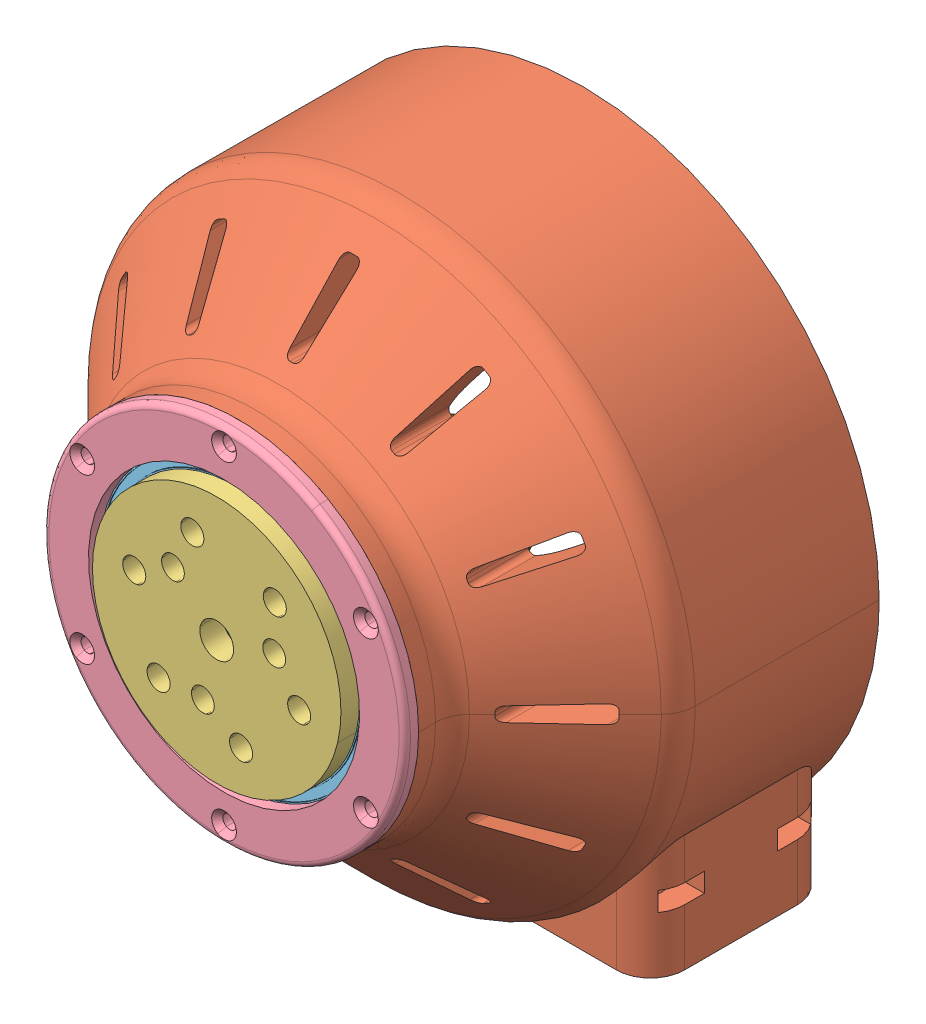
SolidWorks assembly SpryDrive 8318, configuration Default. Lengths in mm.
Overall size (105 105 68.81).
71 component instances, 27 part files, 0 mates.
Components (placement in the parent):
- sprydrive 8318.STEP-1: sprydrive 8318.STEP [Default] at origin size (130.11 130.11 77.91)
  - MOTOR BACK HOUSING REV01.STEP-1: MOTOR BACK HOUSING REV01.STEP [Default] at (0 0 6) x (0.707107 0.707107 0) z (-0.707107 0.707107 0) size (92 25.2 92) (hidden)
  - MOTOR ROTOR REV01_X8318S.STEP-1: MOTOR ROTOR REV01_X8318S.STEP [Default] at (0 0 6.3) x (-0.302803 -0.953053 0) z (-0.953053 0.302803 0) size (92 33.71 92) (hidden)
  - MOTOR STATOR REV01.STEP-1: MOTOR STATOR REV01.STEP [Default] at (0 0 7.2) x (-0.996782 0.080159 0) z (0.080159 0.996782 0) size (81.2 19.01 81.2) (hidden)
  - MOTOR SHAFT REV01_X8318S.STEP-1: MOTOR SHAFT REV01_X8318S.STEP [Default] at (0 0 3.5) x (0.302803 0.953053 0) z (0.953053 -0.302803 0) size (19.64 50.01 18.94)
  - FRAME REV07_X8318S.STEP-1: FRAME REV07_X8318S.STEP [Default] at origin size (105 105 61.05)
  - OUTPUT PLATE REV05.STEP-1: OUTPUT PLATE REV05.STEP [Default] at (0 0 60.725) x (-0.973223 0.229863 0) z (0 0 1) size (44 44 11.85)
  - BACK PLATE REV05.STEP-1: BACK PLATE REV05.STEP [Default] x (-1 0 0) z (0 -1 0) size (105 7 105) (hidden)
  - BEARING COVER REV04.STEP-1: BEARING COVER REV04.STEP [Default] at (0 0 61.5) x (-0.5 -0.866025 0) z (0 0 1) size (64 64 2.45)
  - ADAPTER PLATE REV05.STEP-1: ADAPTER PLATE REV05.STEP [Default] at (0 0 40) x (-0.953053 0.302803 0) z (0 0 1) size (37 37 3.17) (hidden)
  - MAGNET HOLDER REV02.STEP-1: MAGNET HOLDER REV02.STEP [Default] at (0 0 -2) x (0.97677 0.214292 0) z (0 0 -1) size (24 24 5) (hidden)
  - ENCODER MOUNT REV01.STEP-1: ENCODER MOUNT REV01.STEP [Default] x (-1 0 0) z (0 -1 0) size (35.15 5.5 30) (hidden)
  - 91294A190_BLACK ALLOY STEEL FLAT-HEAD SOCKET CAP SCREW_91294A190.STEP-1: 91294A190_BLACK ALLOY STEEL FLAT-HEAD SOCKET CAP SCREW_91294A190.STEP [Default] at (-20 0 -6.6) x (-1 0 0) z (0 0 -1) size (8 8 10.01) (hidden)
  - 91294A190_BLACK ALLOY STEEL FLAT-HEAD SOCKET CAP SCREW_91294A190.STEP-2: 91294A190_BLACK ALLOY STEEL FLAT-HEAD SOCKET CAP SCREW_91294A190.STEP [Default] at (0 20 -6.6) x (-1 0 0) z (0 0 -1) size (8 8 10.01) (hidden)
  - 91294A190_BLACK ALLOY STEEL FLAT-HEAD SOCKET CAP SCREW_91294A190.STEP-3: 91294A190_BLACK ALLOY STEEL FLAT-HEAD SOCKET CAP SCREW_91294A190.STEP [Default] at (20 0 -6.6) x (-1 0 0) z (0 0 -1) size (8 8 10.01) (hidden)
  - 93395A144_TYPE 316 SS FLAT-HEAD SOCKET CAP SCREW_93395A144.STEP-1: 93395A144_TYPE 316 SS FLAT-HEAD SOCKET CAP SCREW_93395A144.STEP [Default] at (14.0729 8.125 -12.5) x (-1 0 0) z (0 0 -1) size (4 4 10) (hidden)
  - 93395A144_TYPE 316 SS FLAT-HEAD SOCKET CAP SCREW_93395A144.STEP-2: 93395A144_TYPE 316 SS FLAT-HEAD SOCKET CAP SCREW_93395A144.STEP [Default] at (-14.0729 8.125 -12.5) x (-1 0 0) z (0 0 -1) size (4 4 10) (hidden)
  - 93395A144_TYPE 316 SS FLAT-HEAD SOCKET CAP SCREW_93395A144.STEP-3: 93395A144_TYPE 316 SS FLAT-HEAD SOCKET CAP SCREW_93395A144.STEP [Default] at (-14.0729 -8.125 -12.5) x (-1 0 0) z (0 0 -1) size (4 4 10) (hidden)
  - 93395A144_TYPE 316 SS FLAT-HEAD SOCKET CAP SCREW_93395A144.STEP-4: 93395A144_TYPE 316 SS FLAT-HEAD SOCKET CAP SCREW_93395A144.STEP [Default] at (14.0729 -8.125 -12.5) x (-1 0 0) z (0 0 -1) size (4 4 10) (hidden)
  - 6808-2RS BEARING DEEP GROOVE 40x52x7 REV02_4668K161.STEP-1: 6808-2RS BEARING DEEP GROOVE 40x52x7 REV02_4668K161.STEP [Default] at (0 0 58) x (0.843788 0.536676 0) z (0 0 -1) size (52 52 7)
  - AS5048A-AB-1.0-ND ENCODER BOARD.STEP-1: AS5048A-AB-1.0-ND ENCODER BOARD.STEP [Default] at (0 -6.5 -10) x (-1 0 0) z (0 1 0) size (22 2 28) (hidden)
  - AS5048A-AB-1.0-ND MAGNET.STEP-1: AS5048A-AB-1.0-ND MAGNET.STEP [Default] at (0 0 -6.5) x (0.996708 0.081075 0) z (0.081075 -0.996708 0) size (6 2.5 6) (hidden)
  - OUTPUT MOUNTING PLATE REV01.STEP-1: OUTPUT MOUNTING PLATE REV01.STEP [Default] at (0 0 57.55) x (0.287545 -0.957767 0) z (0 0 1) size (35 35 3.17)
  - VERSA PLANET.STEP-1: VERSA PLANET.STEP [Default] at (-7.7426 7.2935 48.85) x (-0.918635 0.395106 0) z (0 0 1) size (16.03 16.01 8)
  - VERSA PLANET.STEP-2: VERSA PLANET.STEP [Default] at (10.1876 3.0586 48.85) x (0.461046 0.887376 0) z (0 0 1) size (16.03 16.01 8)
  - VERSA PLANET.STEP-3: VERSA PLANET.STEP [Default] at (-2.445 -10.352 48.85) x (-0.3211 -0.947045 0) z (0 0 1) size (16.03 16.01 8)
  - VERSA RING - MODIFIED.STEP-1: VERSA RING - MODIFIED.STEP [Default] at (0 0 44.1) x (0 1 0) z (0 0 -1) size (42 42 11.32)
  - 93600A455_METRIC TYPE 316 STAINLESS STEEL DOWEL PIN_93600A455.STEP-1: 93600A455_METRIC TYPE 316 STAINLESS STEEL DOWEL PIN_93600A455.STEP [Default] at (-7.7426 7.2935 53.85) x (0 0 -1) z (0.833244 0.552906 0) size (18 4 4) (hidden)
  - 93600A455_METRIC TYPE 316 STAINLESS STEEL DOWEL PIN_93600A455.STEP-2: 93600A455_METRIC TYPE 316 STAINLESS STEEL DOWEL PIN_93600A455.STEP [Default] at (10.1876 3.0586 53.85) x (0 0 -1) z (0.833244 0.552906 0) size (18 4 4) (hidden)
  - 93600A455_METRIC TYPE 316 STAINLESS STEEL DOWEL PIN_93600A455.STEP-3: 93600A455_METRIC TYPE 316 STAINLESS STEEL DOWEL PIN_93600A455.STEP [Default] at (-2.445 -10.352 53.85) x (0 0 -1) z (-0.663244 0.748403 0) size (18 4 4) (hidden)
  - 90358A002_METRIC STL ULTRA-LOW-PROFILE SCKT HEAD SCREW_90358A002.STEP-1: 90358A002_METRIC STL ULTRA-LOW-PROFILE SCKT HEAD SCREW_90358A002.STEP [Default] at (-4.6934 -14.7723 39.175) x (0 0 -1) z (-0.620938 -0.783859 0) size (9.01 5.5 5.5) (hidden)
  - 90358A002_METRIC STL ULTRA-LOW-PROFILE SCKT HEAD SCREW_90358A002.STEP-2: 90358A002_METRIC STL ULTRA-LOW-PROFILE SCKT HEAD SCREW_90358A002.STEP [Default] at (14.7723 -4.6934 39.175) x (0 0 -1) z (-0.964603 -0.263707 0) size (9.01 5.5 5.5) (hidden)
  - 90358A002_METRIC STL ULTRA-LOW-PROFILE SCKT HEAD SCREW_90358A002.STEP-3: 90358A002_METRIC STL ULTRA-LOW-PROFILE SCKT HEAD SCREW_90358A002.STEP [Default] at (4.6934 14.7723 39.175) x (0 0 -1) z (-0.993401 0.11469 0) size (9.01 5.5 5.5) (hidden)
  - 90358A002_METRIC STL ULTRA-LOW-PROFILE SCKT HEAD SCREW_90358A002.STEP-4: 90358A002_METRIC STL ULTRA-LOW-PROFILE SCKT HEAD SCREW_90358A002.STEP [Default] at (-14.7723 4.6934 39.175) x (0 0 -1) z (-0.942672 -0.333722 0) size (9.01 5.5 5.5) (hidden)
  - 93395A144_TYPE 316 SS FLAT-HEAD SOCKET CAP SCREW_93395A144.STEP-5: 93395A144_TYPE 316 SS FLAT-HEAD SOCKET CAP SCREW_93395A144.STEP [Default] at (0 29 63.5) size (4 4 10) (hidden)
  - 93395A144_TYPE 316 SS FLAT-HEAD SOCKET CAP SCREW_93395A144.STEP-6: 93395A144_TYPE 316 SS FLAT-HEAD SOCKET CAP SCREW_93395A144.STEP [Default] at (25.1147 14.5 63.5) size (4 4 10) (hidden)
  - 93395A144_TYPE 316 SS FLAT-HEAD SOCKET CAP SCREW_93395A144.STEP-7: 93395A144_TYPE 316 SS FLAT-HEAD SOCKET CAP SCREW_93395A144.STEP [Default] at (-25.1147 14.5 63.5) size (4 4 10) (hidden)
  - 93395A144_TYPE 316 SS FLAT-HEAD SOCKET CAP SCREW_93395A144.STEP-8: 93395A144_TYPE 316 SS FLAT-HEAD SOCKET CAP SCREW_93395A144.STEP [Default] at (25.1147 -14.5 63.5) size (4 4 10) (hidden)
  - 94459A110_BRASS HEAT-SET INSERT FOR PLASTIC_94459A110.STEP-1: 94459A110_BRASS HEAT-SET INSERT FOR PLASTIC_94459A110.STEP [Default] at (25.1147 14.5 58.55) x (-0.767549 -0.640991 0) z (-0.640991 0.767549 0) size (3.69 2.5 3.69) (hidden)
  - 94459A110_BRASS HEAT-SET INSERT FOR PLASTIC_94459A110.STEP-2: 94459A110_BRASS HEAT-SET INSERT FOR PLASTIC_94459A110.STEP [Default] at (0 29 58.55) x (-0.593469 0.804857 0) z (0.804857 0.593469 0) size (3.69 2.5 3.69) (hidden)
  - 94459A110_BRASS HEAT-SET INSERT FOR PLASTIC_94459A110.STEP-3: 94459A110_BRASS HEAT-SET INSERT FOR PLASTIC_94459A110.STEP [Default] at (0 -29 58.55) x (-0.997114 0.075912 0) z (0.075912 0.997114 0) size (3.69 2.5 3.69) (hidden)
  - 94459A110_BRASS HEAT-SET INSERT FOR PLASTIC_94459A110.STEP-4: 94459A110_BRASS HEAT-SET INSERT FOR PLASTIC_94459A110.STEP [Default] at (25.1147 -14.5 58.55) x (0.079432 0.99684 0) z (0.99684 -0.079432 0) size (3.69 2.5 3.69) (hidden)
  - 93395A144_TYPE 316 SS FLAT-HEAD SOCKET CAP SCREW_93395A144.STEP-9: 93395A144_TYPE 316 SS FLAT-HEAD SOCKET CAP SCREW_93395A144.STEP [Default] at (0 -49.5 -7) x (-1 0 0) z (0 0 -1) size (4 4 10) (hidden)
  - 93395A144_TYPE 316 SS FLAT-HEAD SOCKET CAP SCREW_93395A144.STEP-10: 93395A144_TYPE 316 SS FLAT-HEAD SOCKET CAP SCREW_93395A144.STEP [Default] at (-42.8683 -24.75 -7) x (-1 0 0) z (0 0 -1) size (4 4 10) (hidden)
  - 93395A144_TYPE 316 SS FLAT-HEAD SOCKET CAP SCREW_93395A144.STEP-11: 93395A144_TYPE 316 SS FLAT-HEAD SOCKET CAP SCREW_93395A144.STEP [Default] at (42.8683 -24.75 -7) x (-1 0 0) z (0 0 -1) size (4 4 10) (hidden)
  - 93395A144_TYPE 316 SS FLAT-HEAD SOCKET CAP SCREW_93395A144.STEP-12: 93395A144_TYPE 316 SS FLAT-HEAD SOCKET CAP SCREW_93395A144.STEP [Default] at (0 49.5 -7) x (-1 0 0) z (0 0 -1) size (4 4 10) (hidden)
  - 93395A144_TYPE 316 SS FLAT-HEAD SOCKET CAP SCREW_93395A144.STEP-13: 93395A144_TYPE 316 SS FLAT-HEAD SOCKET CAP SCREW_93395A144.STEP [Default] at (-42.8683 24.75 -7) x (-1 0 0) z (0 0 -1) size (4 4 10) (hidden)
  - 93395A144_TYPE 316 SS FLAT-HEAD SOCKET CAP SCREW_93395A144.STEP-14: 93395A144_TYPE 316 SS FLAT-HEAD SOCKET CAP SCREW_93395A144.STEP [Default] at (42.8683 24.75 -7) x (-1 0 0) z (0 0 -1) size (4 4 10) (hidden)
  - 94459A110_BRASS HEAT-SET INSERT FOR PLASTIC_94459A110.STEP-5: 94459A110_BRASS HEAT-SET INSERT FOR PLASTIC_94459A110.STEP [Default] at (42.8683 -24.75 2.5) x (0.239904 0.970797 0) z (-0.970797 0.239904 0) size (3.69 2.5 3.69) (hidden)
  - 94459A110_BRASS HEAT-SET INSERT FOR PLASTIC_94459A110.STEP-6: 94459A110_BRASS HEAT-SET INSERT FOR PLASTIC_94459A110.STEP [Default] at (0 49.5 2.5) x (0.239904 0.970797 0) z (-0.970797 0.239904 0) size (3.69 2.5 3.69) (hidden)
  - 94459A110_BRASS HEAT-SET INSERT FOR PLASTIC_94459A110.STEP-7: 94459A110_BRASS HEAT-SET INSERT FOR PLASTIC_94459A110.STEP [Default] at (42.8683 24.75 2.5) x (0.239904 0.970797 0) z (-0.970797 0.239904 0) size (3.69 2.5 3.69) (hidden)
  - 94459A110_BRASS HEAT-SET INSERT FOR PLASTIC_94459A110.STEP-8: 94459A110_BRASS HEAT-SET INSERT FOR PLASTIC_94459A110.STEP [Default] at (-42.8683 -24.75 2.5) x (0.239904 0.970797 0) z (-0.970797 0.239904 0) size (3.69 2.5 3.69) (hidden)
  - 94459A110_BRASS HEAT-SET INSERT FOR PLASTIC_94459A110.STEP-9: 94459A110_BRASS HEAT-SET INSERT FOR PLASTIC_94459A110.STEP [Default] at (0 -49.5 2.5) x (0.239904 0.970797 0) z (-0.970797 0.239904 0) size (3.69 2.5 3.69) (hidden)
  - 94459A110_BRASS HEAT-SET INSERT FOR PLASTIC_94459A110.STEP-10: 94459A110_BRASS HEAT-SET INSERT FOR PLASTIC_94459A110.STEP [Default] at (-42.8683 24.75 2.5) x (0.239904 0.970797 0) z (-0.970797 0.239904 0) size (3.69 2.5 3.69) (hidden)
  - 91294A190_BLACK ALLOY STEEL FLAT-HEAD SOCKET CAP SCREW_91294A190.STEP-4: 91294A190_BLACK ALLOY STEEL FLAT-HEAD SOCKET CAP SCREW_91294A190.STEP [Default] at (0 -20 -6.6) x (-1 0 0) z (0 0 -1) size (8 8 10.01) (hidden)
  - 93395A144_TYPE 316 SS FLAT-HEAD SOCKET CAP SCREW_93395A144.STEP-15: 93395A144_TYPE 316 SS FLAT-HEAD SOCKET CAP SCREW_93395A144.STEP [Default] at (0 -29 63.5) size (4 4 10) (hidden)
  - 93395A144_TYPE 316 SS FLAT-HEAD SOCKET CAP SCREW_93395A144.STEP-16: 93395A144_TYPE 316 SS FLAT-HEAD SOCKET CAP SCREW_93395A144.STEP [Default] at (-25.1147 -14.5 63.5) size (4 4 10) (hidden)
  - 90710A025_TYPE 18-8 SS THIN HEX NUT - DIN 439B_90710A025.STEP-1: 90710A025_TYPE 18-8 SS THIN HEX NUT - DIN 439B_90710A025.STEP [Default] at (9 -5.5 -12.3) x (-0.866025 0.5 0) z (-0.5 -0.866025 0) size (5.78 1.62 5.78) (hidden)
  - 90710A025_TYPE 18-8 SS THIN HEX NUT - DIN 439B_90710A025.STEP-2: 90710A025_TYPE 18-8 SS THIN HEX NUT - DIN 439B_90710A025.STEP [Default] at (-9 -5.5 -12.3) x (-0.866025 0.5 0) z (-0.5 -0.866025 0) size (5.78 1.62 5.78) (hidden)
  - 90710A025_TYPE 18-8 SS THIN HEX NUT - DIN 439B_90710A025.STEP-3: 90710A025_TYPE 18-8 SS THIN HEX NUT - DIN 439B_90710A025.STEP [Default] at (-9 5.5 -12.3) x (-0.866025 0.5 0) z (-0.5 -0.866025 0) size (5.78 1.62 5.78) (hidden)
  - 90710A025_TYPE 18-8 SS THIN HEX NUT - DIN 439B_90710A025.STEP-4: 90710A025_TYPE 18-8 SS THIN HEX NUT - DIN 439B_90710A025.STEP [Default] at (9 5.5 -12.3) x (-0.866025 0.5 0) z (-0.5 -0.866025 0) size (5.78 1.62 5.78) (hidden)
  - NMB L2112KK BEARING.STEP-1: NMB L2112KK BEARING.STEP [Default] at (0 0 18.7) x (0.90792 -0.419144 0) z (0 0 1) size (21 21 5)
  - NMB L2112KK BEARING.STEP-2: NMB L2112KK BEARING.STEP [Default] at (0 0 3) x (0.990401 -0.138221 0) z (0 0 1) size (21 21 5)
  - VERSA CARRIER.STEP-1: VERSA CARRIER.STEP [Default] at (0 0 55.2) x (0.685678 0.727905 0) z (0 0 1) size (34.7 34.7 4.7)
  - VERSA SUN GEAR, 12T.STEP-1: VERSA SUN GEAR, 12T.STEP [Default] at (0 0 46.35) x (0.939988 -0.341209 0) z (0 0 1) size (14.47 14.47 12.71)
  - 90592A090_STEEL HEX NUT_90592A090.STEP-1: 90592A090_STEEL HEX NUT_90592A090.STEP [Default] at (40 -34.4 28) x (0 0 -1) z (1 0 0) size (8.09 3.22 8.1) (hidden)
  - 90592A090_STEEL HEX NUT_90592A090.STEP-2: 90592A090_STEEL HEX NUT_90592A090.STEP [Default] at (40 -34.4 8) x (0 0 -1) z (1 0 0) size (8.09 3.22 8.1) (hidden)
  - 90592A090_STEEL HEX NUT_90592A090.STEP-3: 90592A090_STEEL HEX NUT_90592A090.STEP [Default] at (-40 -34.2 8) x (0 0 1) z (1 0 0) size (8.09 3.22 8.1) (hidden)
  - 90592A090_STEEL HEX NUT_90592A090.STEP-4: 90592A090_STEEL HEX NUT_90592A090.STEP [Default] at (-40 -34.4 28) x (0 0 1) z (-1 0 0) size (8.09 3.22 8.1) (hidden)
  - 94459A110_BRASS HEAT-SET INSERT FOR PLASTIC_94459A110.STEP-11: 94459A110_BRASS HEAT-SET INSERT FOR PLASTIC_94459A110.STEP [Default] at (-25.1147 -14.5 58.55) x (-0.532301 0.846555 0) z (0.846555 0.532301 0) size (3.69 2.5 3.69) (hidden)
  - 94459A110_BRASS HEAT-SET INSERT FOR PLASTIC_94459A110.STEP-12: 94459A110_BRASS HEAT-SET INSERT FOR PLASTIC_94459A110.STEP [Default] at (-25.1147 14.5 58.55) x (-0.588465 0.808522 0) z (0.808522 0.588465 0) size (3.69 2.5 3.69) (hidden)
